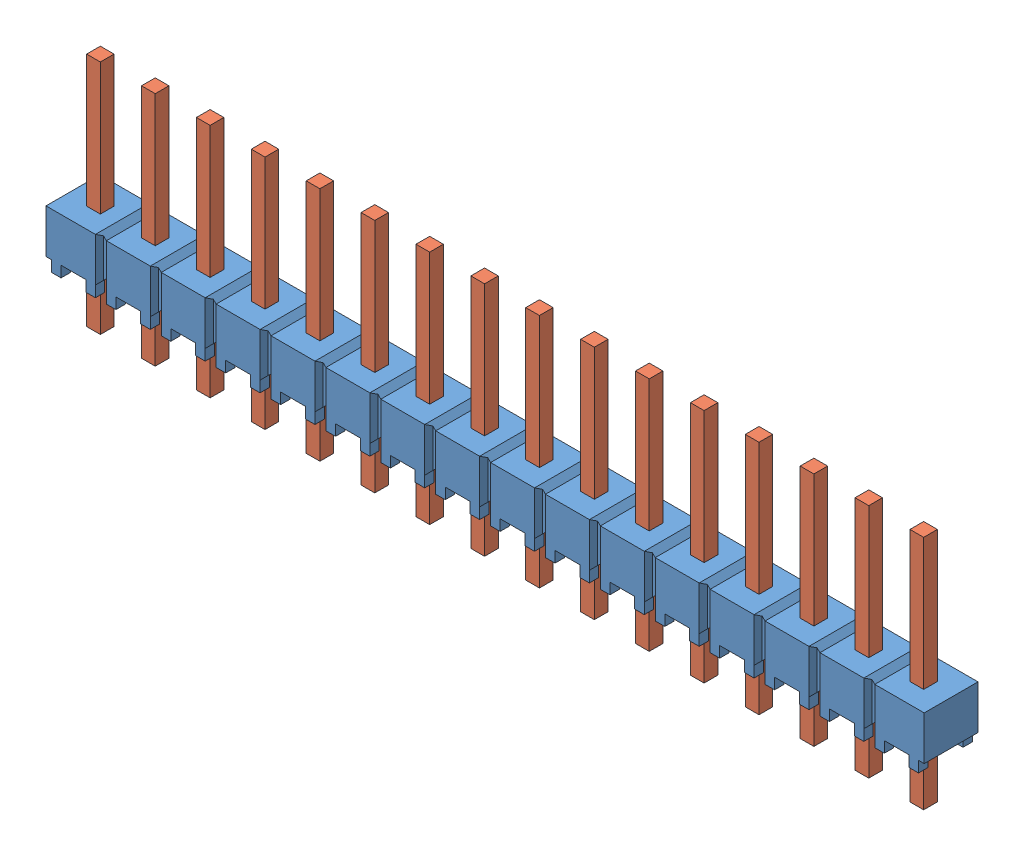
SolidWorks assembly HMTSW_116_07_G_S_240, configuration Default. Lengths in mm.
Overall size (40.64 10.92 2.49).
2 component instances, 2 part files, 0 mates.
Components (placement in the parent):
- _HMTSW_116_07_G_S_240_body_2-1: _HMTSW_116_07_G_S_240_body_2 [Default] at origin size (40.64 2.54 2.49)
- _HMTSW_116_07_S_240_4-1: _HMTSW_116_07_S_240_4 [Default] at (0 -2.286 0) size (38.99 10.92 0.89)
